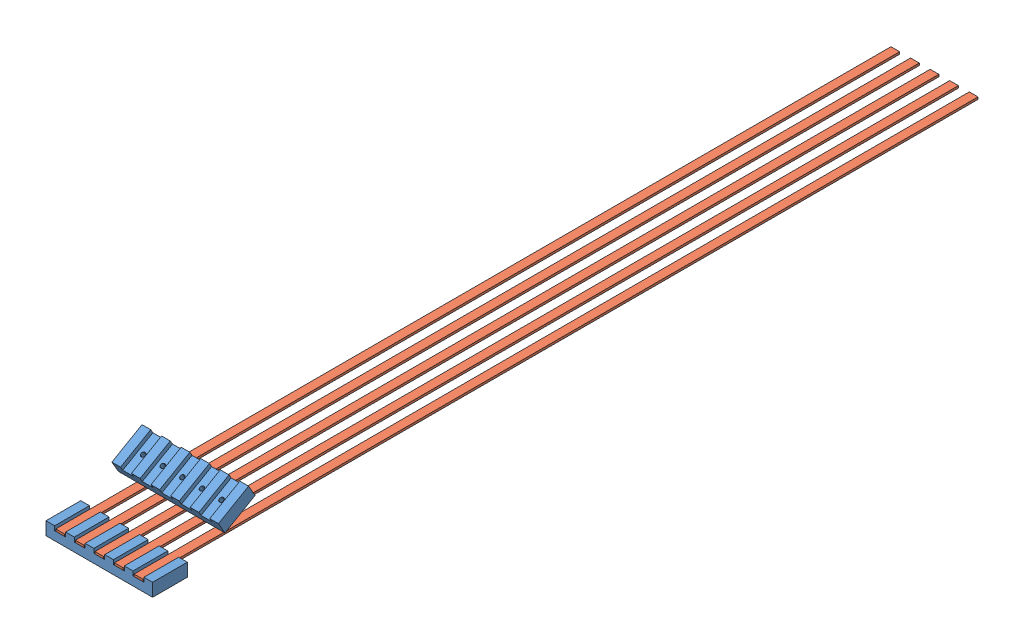
SolidWorks assembly Assem1, configuration Default. Lengths in mm.
Overall size (155.57 70.47 1219.2).
7 component instances, 2 part files, 6 mates.
Components (placement in the parent):
- Bus Bar Holder-1: Bus Bar Holder [Default] at origin size (155.57 19.05 50.8)
- Copper Bus Bar-1: Copper Bus Bar [Default] at (-57.15 7.9375 -584.2) size (12.7 3.17 1219.2)
- Copper Bus Bar-2: Copper Bus Bar [Default] at (-28.575 7.9375 -584.2) size (12.7 3.17 1219.2)
- Copper Bus Bar-3: Copper Bus Bar [Default] at (0 7.9375 -584.2) size (12.7 3.17 1219.2)
- Copper Bus Bar-4: Copper Bus Bar [Default] at (28.575 7.9375 -584.2) size (12.7 3.17 1219.2)
- Copper Bus Bar-5: Copper Bus Bar [Default] at (57.15 7.9375 -584.2) size (12.7 3.17 1219.2)
- Bus Bar Holder-2: Bus Bar Holder [Default] at (0 40.4243 -99.0962) x (1 0 0) z (0 -0.5 0.866025) size (155.57 19.05 50.8)
Mates (geometry in assembly coordinates):
- Coincident1: coincident anti-aligned: plane of Bus Bar Holder-1 through (0 6.35 25.4) normal (0 1 0); plane of Copper Bus Bar-1 through (-57.15 6.35 -584.2) normal (0 -1 0)
- Width1: width anti-aligned: plane of Copper Bus Bar-1 through (-50.8 9.525 25.4) normal (1 0 0); plane of Bus Bar Holder-1 through (-63.5 9.525 25.4) normal (-1 0 0); plane of Copper Bus Bar-1 through (-49.2125 0 25.4) normal (-1 0 0); plane of Bus Bar Holder-1 through (-65.0875 0 25.4) normal (1 0 0)
- Coincident2: coincident aligned: plane of Bus Bar Holder-1 through (0 0 25.4) normal (0 0 1); plane of Copper Bus Bar-1 through (-63.5 9.525 25.4) normal (0 0 1)
- Coincident3: coincident aligned: plane of Bus Bar Holder-1 through (49.2125 0 25.4) normal (1 0 0); plane of Bus Bar Holder-2 through (49.2125 27.7243 -77.0992) normal (1 0 0)
- Angle1: planar angle = 0.523599 rad aligned: plane of Bus Bar Holder-2 through (0 33.2235 -73.9242) normal (0 0.866025 0.5); plane of Copper Bus Bar-5 through (57.15 9.525 -584.2) normal (0 1 0)
- Distance1: distance = 12.7 mm: plane of Copper Bus Bar-5 through (57.15 9.525 -584.2) normal (0 1 0); line of Bus Bar Holder-2 through (-77.7875 22.225 -80.2742) axis (1 0 0)
